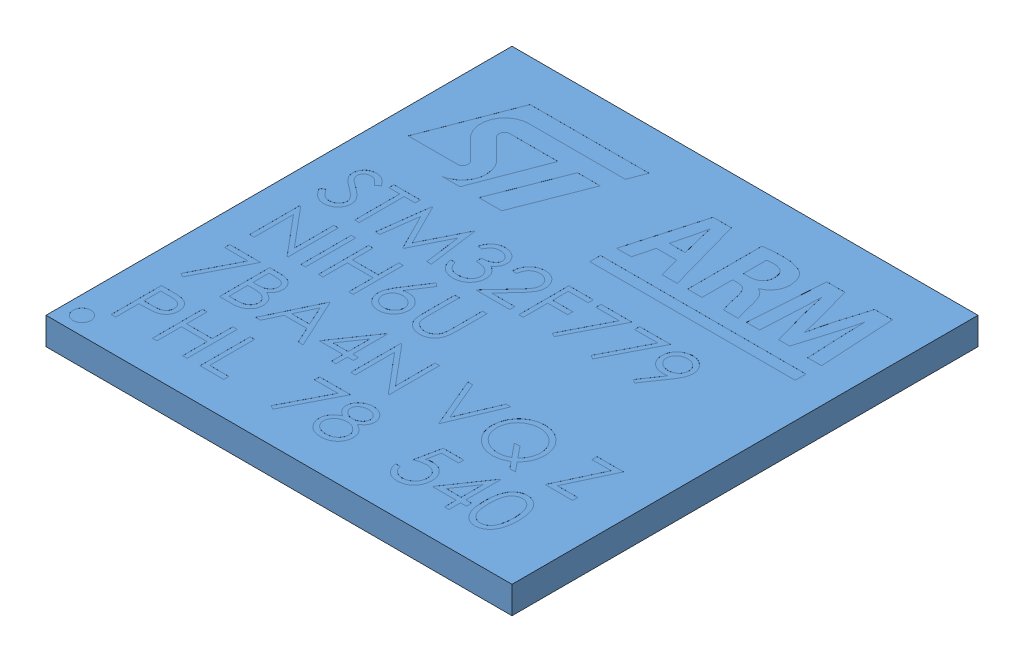
SolidWorks assembly STM32F779NIHx, configuration Default. Lengths in mm.
Overall size (13 0.96 13).
217 component instances, 2 part files, 3 mates.
Components (placement in the parent):
- Part1-1: Part1 [Default] at (-6.3865 6.105 16.3707) size (13 0.76 13)
- ball-1: ball [Default] at (5.7135 6.105 15.4707) x (-0.992109 0 0.125382) z (0.125382 0 0.992109) size (0.4 0.2 0.4)
- ball-2: ball [Default] at (4.9135 6.105 15.4707) x (-0.992109 0 0.125382) z (0.125382 0 0.992109) size (0.4 0.2 0.4)
- ball-3: ball [Default] at (4.1135 6.105 15.4707) x (-0.992109 0 0.125382) z (0.125382 0 0.992109) size (0.4 0.2 0.4)
- ball-4: ball [Default] at (3.3135 6.105 15.4707) x (-0.992109 0 0.125382) z (0.125382 0 0.992109) size (0.4 0.2 0.4)
- ball-5: ball [Default] at (2.5135 6.105 15.4707) x (-0.992109 0 0.125382) z (0.125382 0 0.992109) size (0.4 0.2 0.4)
- ball-6: ball [Default] at (1.7135 6.105 15.4707) x (-0.992109 0 0.125382) z (0.125382 0 0.992109) size (0.4 0.2 0.4)
- ball-7: ball [Default] at (0.9135 6.105 15.4707) x (-0.992109 0 0.125382) z (0.125382 0 0.992109) size (0.4 0.2 0.4)
- ball-8: ball [Default] at (0.1135 6.105 15.4707) x (-0.992109 0 0.125382) z (0.125382 0 0.992109) size (0.4 0.2 0.4)
- ball-9: ball [Default] at (-0.6865 6.105 15.4707) x (-0.992109 0 0.125382) z (0.125382 0 0.992109) size (0.4 0.2 0.4)
- ball-10: ball [Default] at (-1.4865 6.105 15.4707) x (-0.992109 0 0.125382) z (0.125382 0 0.992109) size (0.4 0.2 0.4)
- ball-11: ball [Default] at (-2.2865 6.105 15.4707) x (-0.992109 0 0.125382) z (0.125382 0 0.992109) size (0.4 0.2 0.4)
- ball-12: ball [Default] at (-3.0865 6.105 15.4707) x (-0.992109 0 0.125382) z (0.125382 0 0.992109) size (0.4 0.2 0.4)
- ball-13: ball [Default] at (-3.8865 6.105 15.4707) x (-0.992109 0 0.125382) z (0.125382 0 0.992109) size (0.4 0.2 0.4)
- ball-14: ball [Default] at (-4.6865 6.105 15.4707) x (-0.992109 0 0.125382) z (0.125382 0 0.992109) size (0.4 0.2 0.4)
- ball-15: ball [Default] at (-5.4865 6.105 15.4707) x (-0.992109 0 0.125382) z (0.125382 0 0.992109) size (0.4 0.2 0.4)
- ball-16: ball [Default] at (5.7135 6.105 14.6707) x (-0.992109 0 0.125382) z (0.125382 0 0.992109) size (0.4 0.2 0.4)
- ball-17: ball [Default] at (5.7135 6.105 13.8707) x (-0.992109 0 0.125382) z (0.125382 0 0.992109) size (0.4 0.2 0.4)
- ball-18: ball [Default] at (5.7135 6.105 13.0707) x (-0.992109 0 0.125382) z (0.125382 0 0.992109) size (0.4 0.2 0.4)
- ball-19: ball [Default] at (5.7135 6.105 12.2707) x (-0.992109 0 0.125382) z (0.125382 0 0.992109) size (0.4 0.2 0.4)
- ball-20: ball [Default] at (5.7135 6.105 11.4707) x (-0.992109 0 0.125382) z (0.125382 0 0.992109) size (0.4 0.2 0.4)
- ball-21: ball [Default] at (5.7135 6.105 10.6707) x (-0.992109 0 0.125382) z (0.125382 0 0.992109) size (0.4 0.2 0.4)
- ball-22: ball [Default] at (5.7135 6.105 9.8707) x (-0.992109 0 0.125382) z (0.125382 0 0.992109) size (0.4 0.2 0.4)
- ball-23: ball [Default] at (5.7135 6.105 9.0707) x (-0.992109 0 0.125382) z (0.125382 0 0.992109) size (0.4 0.2 0.4)
- ball-24: ball [Default] at (5.7135 6.105 8.2707) x (-0.992109 0 0.125382) z (0.125382 0 0.992109) size (0.4 0.2 0.4)
- ball-25: ball [Default] at (5.7135 6.105 7.4707) x (-0.992109 0 0.125382) z (0.125382 0 0.992109) size (0.4 0.2 0.4)
- ball-26: ball [Default] at (5.7135 6.105 6.6707) x (-0.992109 0 0.125382) z (0.125382 0 0.992109) size (0.4 0.2 0.4)
- ball-27: ball [Default] at (5.7135 6.105 5.8707) x (-0.992109 0 0.125382) z (0.125382 0 0.992109) size (0.4 0.2 0.4)
- ball-28: ball [Default] at (5.7135 6.105 5.0707) x (-0.992109 0 0.125382) z (0.125382 0 0.992109) size (0.4 0.2 0.4)
- ball-29: ball [Default] at (5.7135 6.105 4.2707) x (-0.992109 0 0.125382) z (0.125382 0 0.992109) size (0.4 0.2 0.4)
- ball-30: ball [Default] at (4.9135 6.105 14.6707) x (-0.992109 0 0.125382) z (0.125382 0 0.992109) size (0.4 0.2 0.4)
- ball-31: ball [Default] at (4.9135 6.105 13.8707) x (-0.992109 0 0.125382) z (0.125382 0 0.992109) size (0.4 0.2 0.4)
- ball-32: ball [Default] at (4.9135 6.105 13.0707) x (-0.992109 0 0.125382) z (0.125382 0 0.992109) size (0.4 0.2 0.4)
- ball-33: ball [Default] at (4.9135 6.105 12.2707) x (-0.992109 0 0.125382) z (0.125382 0 0.992109) size (0.4 0.2 0.4)
- ball-34: ball [Default] at (4.9135 6.105 11.4707) x (-0.992109 0 0.125382) z (0.125382 0 0.992109) size (0.4 0.2 0.4)
- ball-35: ball [Default] at (4.9135 6.105 10.6707) x (-0.992109 0 0.125382) z (0.125382 0 0.992109) size (0.4 0.2 0.4)
- ball-36: ball [Default] at (4.9135 6.105 9.8707) x (-0.992109 0 0.125382) z (0.125382 0 0.992109) size (0.4 0.2 0.4)
- ball-37: ball [Default] at (4.9135 6.105 9.0707) x (-0.992109 0 0.125382) z (0.125382 0 0.992109) size (0.4 0.2 0.4)
- ball-38: ball [Default] at (4.9135 6.105 8.2707) x (-0.992109 0 0.125382) z (0.125382 0 0.992109) size (0.4 0.2 0.4)
- ball-39: ball [Default] at (4.9135 6.105 7.4707) x (-0.992109 0 0.125382) z (0.125382 0 0.992109) size (0.4 0.2 0.4)
- ball-40: ball [Default] at (4.9135 6.105 6.6707) x (-0.992109 0 0.125382) z (0.125382 0 0.992109) size (0.4 0.2 0.4)
- ball-41: ball [Default] at (4.9135 6.105 5.8707) x (-0.992109 0 0.125382) z (0.125382 0 0.992109) size (0.4 0.2 0.4)
- ball-42: ball [Default] at (4.9135 6.105 5.0707) x (-0.992109 0 0.125382) z (0.125382 0 0.992109) size (0.4 0.2 0.4)
- ball-43: ball [Default] at (4.9135 6.105 4.2707) x (-0.992109 0 0.125382) z (0.125382 0 0.992109) size (0.4 0.2 0.4)
- ball-44: ball [Default] at (4.1135 6.105 14.6707) x (-0.992109 0 0.125382) z (0.125382 0 0.992109) size (0.4 0.2 0.4)
- ball-45: ball [Default] at (4.1135 6.105 13.8707) x (-0.992109 0 0.125382) z (0.125382 0 0.992109) size (0.4 0.2 0.4)
- ball-46: ball [Default] at (4.1135 6.105 13.0707) x (-0.992109 0 0.125382) z (0.125382 0 0.992109) size (0.4 0.2 0.4)
- ball-47: ball [Default] at (4.1135 6.105 12.2707) x (-0.992109 0 0.125382) z (0.125382 0 0.992109) size (0.4 0.2 0.4)
- ball-48: ball [Default] at (4.1135 6.105 11.4707) x (-0.992109 0 0.125382) z (0.125382 0 0.992109) size (0.4 0.2 0.4)
- ball-49: ball [Default] at (4.1135 6.105 10.6707) x (-0.992109 0 0.125382) z (0.125382 0 0.992109) size (0.4 0.2 0.4)
- ball-50: ball [Default] at (4.1135 6.105 9.8707) x (-0.992109 0 0.125382) z (0.125382 0 0.992109) size (0.4 0.2 0.4)
- ball-51: ball [Default] at (4.1135 6.105 9.0707) x (-0.992109 0 0.125382) z (0.125382 0 0.992109) size (0.4 0.2 0.4)
- ball-52: ball [Default] at (4.1135 6.105 8.2707) x (-0.992109 0 0.125382) z (0.125382 0 0.992109) size (0.4 0.2 0.4)
- ball-53: ball [Default] at (4.1135 6.105 7.4707) x (-0.992109 0 0.125382) z (0.125382 0 0.992109) size (0.4 0.2 0.4)
- ball-54: ball [Default] at (4.1135 6.105 6.6707) x (-0.992109 0 0.125382) z (0.125382 0 0.992109) size (0.4 0.2 0.4)
- ball-55: ball [Default] at (4.1135 6.105 5.8707) x (-0.992109 0 0.125382) z (0.125382 0 0.992109) size (0.4 0.2 0.4)
- ball-56: ball [Default] at (4.1135 6.105 5.0707) x (-0.992109 0 0.125382) z (0.125382 0 0.992109) size (0.4 0.2 0.4)
- ball-57: ball [Default] at (4.1135 6.105 4.2707) x (-0.992109 0 0.125382) z (0.125382 0 0.992109) size (0.4 0.2 0.4)
- ball-58: ball [Default] at (3.3135 6.105 14.6707) x (-0.992109 0 0.125382) z (0.125382 0 0.992109) size (0.4 0.2 0.4)
- ball-59: ball [Default] at (3.3135 6.105 13.8707) x (-0.992109 0 0.125382) z (0.125382 0 0.992109) size (0.4 0.2 0.4)
- ball-60: ball [Default] at (3.3135 6.105 13.0707) x (-0.992109 0 0.125382) z (0.125382 0 0.992109) size (0.4 0.2 0.4)
- ball-61: ball [Default] at (3.3135 6.105 12.2707) x (-0.992109 0 0.125382) z (0.125382 0 0.992109) size (0.4 0.2 0.4)
- ball-62: ball [Default] at (3.3135 6.105 11.4707) x (-0.992109 0 0.125382) z (0.125382 0 0.992109) size (0.4 0.2 0.4)
- ball-63: ball [Default] at (3.3135 6.105 10.6707) x (-0.992109 0 0.125382) z (0.125382 0 0.992109) size (0.4 0.2 0.4)
- ball-64: ball [Default] at (3.3135 6.105 9.8707) x (-0.992109 0 0.125382) z (0.125382 0 0.992109) size (0.4 0.2 0.4)
- ball-65: ball [Default] at (3.3135 6.105 9.0707) x (-0.992109 0 0.125382) z (0.125382 0 0.992109) size (0.4 0.2 0.4)
- ball-66: ball [Default] at (3.3135 6.105 8.2707) x (-0.992109 0 0.125382) z (0.125382 0 0.992109) size (0.4 0.2 0.4)
- ball-67: ball [Default] at (3.3135 6.105 7.4707) x (-0.992109 0 0.125382) z (0.125382 0 0.992109) size (0.4 0.2 0.4)
- ball-68: ball [Default] at (3.3135 6.105 6.6707) x (-0.992109 0 0.125382) z (0.125382 0 0.992109) size (0.4 0.2 0.4)
- ball-69: ball [Default] at (3.3135 6.105 5.8707) x (-0.992109 0 0.125382) z (0.125382 0 0.992109) size (0.4 0.2 0.4)
- ball-70: ball [Default] at (3.3135 6.105 5.0707) x (-0.992109 0 0.125382) z (0.125382 0 0.992109) size (0.4 0.2 0.4)
- ball-71: ball [Default] at (3.3135 6.105 4.2707) x (-0.992109 0 0.125382) z (0.125382 0 0.992109) size (0.4 0.2 0.4)
- ball-72: ball [Default] at (2.5135 6.105 14.6707) x (-0.992109 0 0.125382) z (0.125382 0 0.992109) size (0.4 0.2 0.4)
- ball-73: ball [Default] at (2.5135 6.105 13.8707) x (-0.992109 0 0.125382) z (0.125382 0 0.992109) size (0.4 0.2 0.4)
- ball-74: ball [Default] at (2.5135 6.105 13.0707) x (-0.992109 0 0.125382) z (0.125382 0 0.992109) size (0.4 0.2 0.4)
- ball-75: ball [Default] at (2.5135 6.105 12.2707) x (-0.992109 0 0.125382) z (0.125382 0 0.992109) size (0.4 0.2 0.4)
- ball-76: ball [Default] at (2.5135 6.105 11.4707) x (-0.992109 0 0.125382) z (0.125382 0 0.992109) size (0.4 0.2 0.4)
- ball-77: ball [Default] at (2.5135 6.105 10.6707) x (-0.992109 0 0.125382) z (0.125382 0 0.992109) size (0.4 0.2 0.4)
- ball-78: ball [Default] at (2.5135 6.105 9.8707) x (-0.992109 0 0.125382) z (0.125382 0 0.992109) size (0.4 0.2 0.4)
- ball-79: ball [Default] at (2.5135 6.105 9.0707) x (-0.992109 0 0.125382) z (0.125382 0 0.992109) size (0.4 0.2 0.4)
- ball-80: ball [Default] at (2.5135 6.105 8.2707) x (-0.992109 0 0.125382) z (0.125382 0 0.992109) size (0.4 0.2 0.4)
- ball-81: ball [Default] at (2.5135 6.105 7.4707) x (-0.992109 0 0.125382) z (0.125382 0 0.992109) size (0.4 0.2 0.4)
- ball-82: ball [Default] at (2.5135 6.105 6.6707) x (-0.992109 0 0.125382) z (0.125382 0 0.992109) size (0.4 0.2 0.4)
- ball-83: ball [Default] at (2.5135 6.105 5.8707) x (-0.992109 0 0.125382) z (0.125382 0 0.992109) size (0.4 0.2 0.4)
- ball-84: ball [Default] at (2.5135 6.105 5.0707) x (-0.992109 0 0.125382) z (0.125382 0 0.992109) size (0.4 0.2 0.4)
- ball-85: ball [Default] at (2.5135 6.105 4.2707) x (-0.992109 0 0.125382) z (0.125382 0 0.992109) size (0.4 0.2 0.4)
- ball-86: ball [Default] at (1.7135 6.105 14.6707) x (-0.992109 0 0.125382) z (0.125382 0 0.992109) size (0.4 0.2 0.4)
- ball-87: ball [Default] at (1.7135 6.105 13.8707) x (-0.992109 0 0.125382) z (0.125382 0 0.992109) size (0.4 0.2 0.4)
- ball-88: ball [Default] at (1.7135 6.105 13.0707) x (-0.992109 0 0.125382) z (0.125382 0 0.992109) size (0.4 0.2 0.4)
- ball-89: ball [Default] at (1.7135 6.105 12.2707) x (-0.992109 0 0.125382) z (0.125382 0 0.992109) size (0.4 0.2 0.4)
- ball-90: ball [Default] at (1.7135 6.105 11.4707) x (-0.992109 0 0.125382) z (0.125382 0 0.992109) size (0.4 0.2 0.4)
- ball-91: ball [Default] at (1.7135 6.105 10.6707) x (-0.992109 0 0.125382) z (0.125382 0 0.992109) size (0.4 0.2 0.4)
- ball-92: ball [Default] at (1.7135 6.105 9.8707) x (-0.992109 0 0.125382) z (0.125382 0 0.992109) size (0.4 0.2 0.4)
- ball-93: ball [Default] at (1.7135 6.105 9.0707) x (-0.992109 0 0.125382) z (0.125382 0 0.992109) size (0.4 0.2 0.4)
- ball-94: ball [Default] at (1.7135 6.105 8.2707) x (-0.992109 0 0.125382) z (0.125382 0 0.992109) size (0.4 0.2 0.4)
- ball-95: ball [Default] at (1.7135 6.105 7.4707) x (-0.992109 0 0.125382) z (0.125382 0 0.992109) size (0.4 0.2 0.4)
- ball-96: ball [Default] at (1.7135 6.105 6.6707) x (-0.992109 0 0.125382) z (0.125382 0 0.992109) size (0.4 0.2 0.4)
- ball-97: ball [Default] at (1.7135 6.105 5.8707) x (-0.992109 0 0.125382) z (0.125382 0 0.992109) size (0.4 0.2 0.4)
- ball-98: ball [Default] at (1.7135 6.105 5.0707) x (-0.992109 0 0.125382) z (0.125382 0 0.992109) size (0.4 0.2 0.4)
- ball-99: ball [Default] at (1.7135 6.105 4.2707) x (-0.992109 0 0.125382) z (0.125382 0 0.992109) size (0.4 0.2 0.4)
- ball-100: ball [Default] at (0.9135 6.105 14.6707) x (-0.992109 0 0.125382) z (0.125382 0 0.992109) size (0.4 0.2 0.4)
- ball-101: ball [Default] at (0.9135 6.105 13.8707) x (-0.992109 0 0.125382) z (0.125382 0 0.992109) size (0.4 0.2 0.4)
- ball-102: ball [Default] at (0.9135 6.105 13.0707) x (-0.992109 0 0.125382) z (0.125382 0 0.992109) size (0.4 0.2 0.4)
- ball-103: ball [Default] at (0.9135 6.105 12.2707) x (-0.992109 0 0.125382) z (0.125382 0 0.992109) size (0.4 0.2 0.4)
- ball-104: ball [Default] at (0.9135 6.105 11.4707) x (-0.992109 0 0.125382) z (0.125382 0 0.992109) size (0.4 0.2 0.4)
- ball-108: ball [Default] at (0.9135 6.105 8.2707) x (-0.992109 0 0.125382) z (0.125382 0 0.992109) size (0.4 0.2 0.4)
- ball-109: ball [Default] at (0.9135 6.105 7.4707) x (-0.992109 0 0.125382) z (0.125382 0 0.992109) size (0.4 0.2 0.4)
- ball-110: ball [Default] at (0.9135 6.105 6.6707) x (-0.992109 0 0.125382) z (0.125382 0 0.992109) size (0.4 0.2 0.4)
- ball-111: ball [Default] at (0.9135 6.105 5.8707) x (-0.992109 0 0.125382) z (0.125382 0 0.992109) size (0.4 0.2 0.4)
- ball-112: ball [Default] at (0.9135 6.105 5.0707) x (-0.992109 0 0.125382) z (0.125382 0 0.992109) size (0.4 0.2 0.4)
- ball-113: ball [Default] at (0.9135 6.105 4.2707) x (-0.992109 0 0.125382) z (0.125382 0 0.992109) size (0.4 0.2 0.4)
- ball-114: ball [Default] at (0.1135 6.105 14.6707) x (-0.992109 0 0.125382) z (0.125382 0 0.992109) size (0.4 0.2 0.4)
- ball-115: ball [Default] at (0.1135 6.105 13.8707) x (-0.992109 0 0.125382) z (0.125382 0 0.992109) size (0.4 0.2 0.4)
- ball-116: ball [Default] at (0.1135 6.105 13.0707) x (-0.992109 0 0.125382) z (0.125382 0 0.992109) size (0.4 0.2 0.4)
- ball-117: ball [Default] at (0.1135 6.105 12.2707) x (-0.992109 0 0.125382) z (0.125382 0 0.992109) size (0.4 0.2 0.4)
- ball-118: ball [Default] at (0.1135 6.105 11.4707) x (-0.992109 0 0.125382) z (0.125382 0 0.992109) size (0.4 0.2 0.4)
- ball-122: ball [Default] at (0.1135 6.105 8.2707) x (-0.992109 0 0.125382) z (0.125382 0 0.992109) size (0.4 0.2 0.4)
- ball-123: ball [Default] at (0.1135 6.105 7.4707) x (-0.992109 0 0.125382) z (0.125382 0 0.992109) size (0.4 0.2 0.4)
- ball-124: ball [Default] at (0.1135 6.105 6.6707) x (-0.992109 0 0.125382) z (0.125382 0 0.992109) size (0.4 0.2 0.4)
- ball-125: ball [Default] at (0.1135 6.105 5.8707) x (-0.992109 0 0.125382) z (0.125382 0 0.992109) size (0.4 0.2 0.4)
- ball-126: ball [Default] at (0.1135 6.105 5.0707) x (-0.992109 0 0.125382) z (0.125382 0 0.992109) size (0.4 0.2 0.4)
- ball-127: ball [Default] at (0.1135 6.105 4.2707) x (-0.992109 0 0.125382) z (0.125382 0 0.992109) size (0.4 0.2 0.4)
- ball-128: ball [Default] at (-0.6865 6.105 14.6707) x (-0.992109 0 0.125382) z (0.125382 0 0.992109) size (0.4 0.2 0.4)
- ball-129: ball [Default] at (-0.6865 6.105 13.8707) x (-0.992109 0 0.125382) z (0.125382 0 0.992109) size (0.4 0.2 0.4)
- ball-130: ball [Default] at (-0.6865 6.105 13.0707) x (-0.992109 0 0.125382) z (0.125382 0 0.992109) size (0.4 0.2 0.4)
- ball-131: ball [Default] at (-0.6865 6.105 12.2707) x (-0.992109 0 0.125382) z (0.125382 0 0.992109) size (0.4 0.2 0.4)
- ball-132: ball [Default] at (-0.6865 6.105 11.4707) x (-0.992109 0 0.125382) z (0.125382 0 0.992109) size (0.4 0.2 0.4)
- ball-136: ball [Default] at (-0.6865 6.105 8.2707) x (-0.992109 0 0.125382) z (0.125382 0 0.992109) size (0.4 0.2 0.4)
- ball-137: ball [Default] at (-0.6865 6.105 7.4707) x (-0.992109 0 0.125382) z (0.125382 0 0.992109) size (0.4 0.2 0.4)
- ball-138: ball [Default] at (-0.6865 6.105 6.6707) x (-0.992109 0 0.125382) z (0.125382 0 0.992109) size (0.4 0.2 0.4)
- ball-139: ball [Default] at (-0.6865 6.105 5.8707) x (-0.992109 0 0.125382) z (0.125382 0 0.992109) size (0.4 0.2 0.4)
- ball-140: ball [Default] at (-0.6865 6.105 5.0707) x (-0.992109 0 0.125382) z (0.125382 0 0.992109) size (0.4 0.2 0.4)
- ball-141: ball [Default] at (-0.6865 6.105 4.2707) x (-0.992109 0 0.125382) z (0.125382 0 0.992109) size (0.4 0.2 0.4)
- ball-142: ball [Default] at (-1.4865 6.105 14.6707) x (-0.992109 0 0.125382) z (0.125382 0 0.992109) size (0.4 0.2 0.4)
- ball-143: ball [Default] at (-1.4865 6.105 13.8707) x (-0.992109 0 0.125382) z (0.125382 0 0.992109) size (0.4 0.2 0.4)
- ball-144: ball [Default] at (-1.4865 6.105 13.0707) x (-0.992109 0 0.125382) z (0.125382 0 0.992109) size (0.4 0.2 0.4)
- ball-145: ball [Default] at (-1.4865 6.105 12.2707) x (-0.992109 0 0.125382) z (0.125382 0 0.992109) size (0.4 0.2 0.4)
- ball-146: ball [Default] at (-1.4865 6.105 11.4707) x (-0.992109 0 0.125382) z (0.125382 0 0.992109) size (0.4 0.2 0.4)
- ball-147: ball [Default] at (-1.4865 6.105 10.6707) x (-0.992109 0 0.125382) z (0.125382 0 0.992109) size (0.4 0.2 0.4)
- ball-148: ball [Default] at (-1.4865 6.105 9.8707) x (-0.992109 0 0.125382) z (0.125382 0 0.992109) size (0.4 0.2 0.4)
- ball-149: ball [Default] at (-1.4865 6.105 9.0707) x (-0.992109 0 0.125382) z (0.125382 0 0.992109) size (0.4 0.2 0.4)
- ball-150: ball [Default] at (-1.4865 6.105 8.2707) x (-0.992109 0 0.125382) z (0.125382 0 0.992109) size (0.4 0.2 0.4)
- ball-151: ball [Default] at (-1.4865 6.105 7.4707) x (-0.992109 0 0.125382) z (0.125382 0 0.992109) size (0.4 0.2 0.4)
- ball-152: ball [Default] at (-1.4865 6.105 6.6707) x (-0.992109 0 0.125382) z (0.125382 0 0.992109) size (0.4 0.2 0.4)
- ball-153: ball [Default] at (-1.4865 6.105 5.8707) x (-0.992109 0 0.125382) z (0.125382 0 0.992109) size (0.4 0.2 0.4)
- ball-154: ball [Default] at (-1.4865 6.105 5.0707) x (-0.992109 0 0.125382) z (0.125382 0 0.992109) size (0.4 0.2 0.4)
- ball-155: ball [Default] at (-1.4865 6.105 4.2707) x (-0.992109 0 0.125382) z (0.125382 0 0.992109) size (0.4 0.2 0.4)
- ball-156: ball [Default] at (-2.2865 6.105 14.6707) x (-0.992109 0 0.125382) z (0.125382 0 0.992109) size (0.4 0.2 0.4)
- ball-157: ball [Default] at (-2.2865 6.105 13.8707) x (-0.992109 0 0.125382) z (0.125382 0 0.992109) size (0.4 0.2 0.4)
- ball-158: ball [Default] at (-2.2865 6.105 13.0707) x (-0.992109 0 0.125382) z (0.125382 0 0.992109) size (0.4 0.2 0.4)
- ball-159: ball [Default] at (-2.2865 6.105 12.2707) x (-0.992109 0 0.125382) z (0.125382 0 0.992109) size (0.4 0.2 0.4)
- ball-160: ball [Default] at (-2.2865 6.105 11.4707) x (-0.992109 0 0.125382) z (0.125382 0 0.992109) size (0.4 0.2 0.4)
- ball-161: ball [Default] at (-2.2865 6.105 10.6707) x (-0.992109 0 0.125382) z (0.125382 0 0.992109) size (0.4 0.2 0.4)
- ball-162: ball [Default] at (-2.2865 6.105 9.8707) x (-0.992109 0 0.125382) z (0.125382 0 0.992109) size (0.4 0.2 0.4)
- ball-163: ball [Default] at (-2.2865 6.105 9.0707) x (-0.992109 0 0.125382) z (0.125382 0 0.992109) size (0.4 0.2 0.4)
- ball-164: ball [Default] at (-2.2865 6.105 8.2707) x (-0.992109 0 0.125382) z (0.125382 0 0.992109) size (0.4 0.2 0.4)
- ball-165: ball [Default] at (-2.2865 6.105 7.4707) x (-0.992109 0 0.125382) z (0.125382 0 0.992109) size (0.4 0.2 0.4)
- ball-166: ball [Default] at (-2.2865 6.105 6.6707) x (-0.992109 0 0.125382) z (0.125382 0 0.992109) size (0.4 0.2 0.4)
- ball-167: ball [Default] at (-2.2865 6.105 5.8707) x (-0.992109 0 0.125382) z (0.125382 0 0.992109) size (0.4 0.2 0.4)
- ball-168: ball [Default] at (-2.2865 6.105 5.0707) x (-0.992109 0 0.125382) z (0.125382 0 0.992109) size (0.4 0.2 0.4)
- ball-169: ball [Default] at (-2.2865 6.105 4.2707) x (-0.992109 0 0.125382) z (0.125382 0 0.992109) size (0.4 0.2 0.4)
- ball-170: ball [Default] at (-3.0865 6.105 14.6707) x (-0.992109 0 0.125382) z (0.125382 0 0.992109) size (0.4 0.2 0.4)
- ball-171: ball [Default] at (-3.0865 6.105 13.8707) x (-0.992109 0 0.125382) z (0.125382 0 0.992109) size (0.4 0.2 0.4)
- ball-172: ball [Default] at (-3.0865 6.105 13.0707) x (-0.992109 0 0.125382) z (0.125382 0 0.992109) size (0.4 0.2 0.4)
- ball-173: ball [Default] at (-3.0865 6.105 12.2707) x (-0.992109 0 0.125382) z (0.125382 0 0.992109) size (0.4 0.2 0.4)
- ball-174: ball [Default] at (-3.0865 6.105 11.4707) x (-0.992109 0 0.125382) z (0.125382 0 0.992109) size (0.4 0.2 0.4)
- ball-175: ball [Default] at (-3.0865 6.105 10.6707) x (-0.992109 0 0.125382) z (0.125382 0 0.992109) size (0.4 0.2 0.4)
- ball-176: ball [Default] at (-3.0865 6.105 9.8707) x (-0.992109 0 0.125382) z (0.125382 0 0.992109) size (0.4 0.2 0.4)
- ball-177: ball [Default] at (-3.0865 6.105 9.0707) x (-0.992109 0 0.125382) z (0.125382 0 0.992109) size (0.4 0.2 0.4)
- ball-178: ball [Default] at (-3.0865 6.105 8.2707) x (-0.992109 0 0.125382) z (0.125382 0 0.992109) size (0.4 0.2 0.4)
- ball-179: ball [Default] at (-3.0865 6.105 7.4707) x (-0.992109 0 0.125382) z (0.125382 0 0.992109) size (0.4 0.2 0.4)
- ball-180: ball [Default] at (-3.0865 6.105 6.6707) x (-0.992109 0 0.125382) z (0.125382 0 0.992109) size (0.4 0.2 0.4)
- ball-181: ball [Default] at (-3.0865 6.105 5.8707) x (-0.992109 0 0.125382) z (0.125382 0 0.992109) size (0.4 0.2 0.4)
- ball-182: ball [Default] at (-3.0865 6.105 5.0707) x (-0.992109 0 0.125382) z (0.125382 0 0.992109) size (0.4 0.2 0.4)
- ball-183: ball [Default] at (-3.0865 6.105 4.2707) x (-0.992109 0 0.125382) z (0.125382 0 0.992109) size (0.4 0.2 0.4)
- ball-184: ball [Default] at (-3.8865 6.105 14.6707) x (-0.992109 0 0.125382) z (0.125382 0 0.992109) size (0.4 0.2 0.4)
- ball-185: ball [Default] at (-3.8865 6.105 13.8707) x (-0.992109 0 0.125382) z (0.125382 0 0.992109) size (0.4 0.2 0.4)
- ball-186: ball [Default] at (-3.8865 6.105 13.0707) x (-0.992109 0 0.125382) z (0.125382 0 0.992109) size (0.4 0.2 0.4)
- ball-187: ball [Default] at (-3.8865 6.105 12.2707) x (-0.992109 0 0.125382) z (0.125382 0 0.992109) size (0.4 0.2 0.4)
- ball-188: ball [Default] at (-3.8865 6.105 11.4707) x (-0.992109 0 0.125382) z (0.125382 0 0.992109) size (0.4 0.2 0.4)
- ball-189: ball [Default] at (-3.8865 6.105 10.6707) x (-0.992109 0 0.125382) z (0.125382 0 0.992109) size (0.4 0.2 0.4)
- ball-190: ball [Default] at (-3.8865 6.105 9.8707) x (-0.992109 0 0.125382) z (0.125382 0 0.992109) size (0.4 0.2 0.4)
- ball-191: ball [Default] at (-3.8865 6.105 9.0707) x (-0.992109 0 0.125382) z (0.125382 0 0.992109) size (0.4 0.2 0.4)
- ball-192: ball [Default] at (-3.8865 6.105 8.2707) x (-0.992109 0 0.125382) z (0.125382 0 0.992109) size (0.4 0.2 0.4)
- ball-193: ball [Default] at (-3.8865 6.105 7.4707) x (-0.992109 0 0.125382) z (0.125382 0 0.992109) size (0.4 0.2 0.4)
- ball-194: ball [Default] at (-3.8865 6.105 6.6707) x (-0.992109 0 0.125382) z (0.125382 0 0.992109) size (0.4 0.2 0.4)
- ball-195: ball [Default] at (-3.8865 6.105 5.8707) x (-0.992109 0 0.125382) z (0.125382 0 0.992109) size (0.4 0.2 0.4)
- ball-196: ball [Default] at (-3.8865 6.105 5.0707) x (-0.992109 0 0.125382) z (0.125382 0 0.992109) size (0.4 0.2 0.4)
- ball-197: ball [Default] at (-3.8865 6.105 4.2707) x (-0.992109 0 0.125382) z (0.125382 0 0.992109) size (0.4 0.2 0.4)
- ball-198: ball [Default] at (-4.6865 6.105 14.6707) x (-0.992109 0 0.125382) z (0.125382 0 0.992109) size (0.4 0.2 0.4)
- ball-199: ball [Default] at (-4.6865 6.105 13.8707) x (-0.992109 0 0.125382) z (0.125382 0 0.992109) size (0.4 0.2 0.4)
- ball-200: ball [Default] at (-4.6865 6.105 13.0707) x (-0.992109 0 0.125382) z (0.125382 0 0.992109) size (0.4 0.2 0.4)
- ball-201: ball [Default] at (-4.6865 6.105 12.2707) x (-0.992109 0 0.125382) z (0.125382 0 0.992109) size (0.4 0.2 0.4)
- ball-202: ball [Default] at (-4.6865 6.105 11.4707) x (-0.992109 0 0.125382) z (0.125382 0 0.992109) size (0.4 0.2 0.4)
- ball-203: ball [Default] at (-4.6865 6.105 10.6707) x (-0.992109 0 0.125382) z (0.125382 0 0.992109) size (0.4 0.2 0.4)
- ball-204: ball [Default] at (-4.6865 6.105 9.8707) x (-0.992109 0 0.125382) z (0.125382 0 0.992109) size (0.4 0.2 0.4)
- ball-205: ball [Default] at (-4.6865 6.105 9.0707) x (-0.992109 0 0.125382) z (0.125382 0 0.992109) size (0.4 0.2 0.4)
- ball-206: ball [Default] at (-4.6865 6.105 8.2707) x (-0.992109 0 0.125382) z (0.125382 0 0.992109) size (0.4 0.2 0.4)
- ball-207: ball [Default] at (-4.6865 6.105 7.4707) x (-0.992109 0 0.125382) z (0.125382 0 0.992109) size (0.4 0.2 0.4)
- ball-208: ball [Default] at (-4.6865 6.105 6.6707) x (-0.992109 0 0.125382) z (0.125382 0 0.992109) size (0.4 0.2 0.4)
- ball-209: ball [Default] at (-4.6865 6.105 5.8707) x (-0.992109 0 0.125382) z (0.125382 0 0.992109) size (0.4 0.2 0.4)
- ball-210: ball [Default] at (-4.6865 6.105 5.0707) x (-0.992109 0 0.125382) z (0.125382 0 0.992109) size (0.4 0.2 0.4)
- ball-211: ball [Default] at (-4.6865 6.105 4.2707) x (-0.992109 0 0.125382) z (0.125382 0 0.992109) size (0.4 0.2 0.4)
- ball-212: ball [Default] at (-5.4865 6.105 14.6707) x (-0.992109 0 0.125382) z (0.125382 0 0.992109) size (0.4 0.2 0.4)
- ball-213: ball [Default] at (-5.4865 6.105 13.8707) x (-0.992109 0 0.125382) z (0.125382 0 0.992109) size (0.4 0.2 0.4)
- ball-214: ball [Default] at (-5.4865 6.105 13.0707) x (-0.992109 0 0.125382) z (0.125382 0 0.992109) size (0.4 0.2 0.4)
- ball-215: ball [Default] at (-5.4865 6.105 12.2707) x (-0.992109 0 0.125382) z (0.125382 0 0.992109) size (0.4 0.2 0.4)
- ball-216: ball [Default] at (-5.4865 6.105 11.4707) x (-0.992109 0 0.125382) z (0.125382 0 0.992109) size (0.4 0.2 0.4)
- ball-217: ball [Default] at (-5.4865 6.105 10.6707) x (-0.992109 0 0.125382) z (0.125382 0 0.992109) size (0.4 0.2 0.4)
- ball-218: ball [Default] at (-5.4865 6.105 9.8707) x (-0.992109 0 0.125382) z (0.125382 0 0.992109) size (0.4 0.2 0.4)
- ball-219: ball [Default] at (-5.4865 6.105 9.0707) x (-0.992109 0 0.125382) z (0.125382 0 0.992109) size (0.4 0.2 0.4)
- ball-220: ball [Default] at (-5.4865 6.105 8.2707) x (-0.992109 0 0.125382) z (0.125382 0 0.992109) size (0.4 0.2 0.4)
- ball-221: ball [Default] at (-5.4865 6.105 7.4707) x (-0.992109 0 0.125382) z (0.125382 0 0.992109) size (0.4 0.2 0.4)
- ball-222: ball [Default] at (-5.4865 6.105 6.6707) x (-0.992109 0 0.125382) z (0.125382 0 0.992109) size (0.4 0.2 0.4)
- ball-223: ball [Default] at (-5.4865 6.105 5.8707) x (-0.992109 0 0.125382) z (0.125382 0 0.992109) size (0.4 0.2 0.4)
- ball-224: ball [Default] at (-5.4865 6.105 5.0707) x (-0.992109 0 0.125382) z (0.125382 0 0.992109) size (0.4 0.2 0.4)
- ball-225: ball [Default] at (-5.4865 6.105 4.2707) x (-0.992109 0 0.125382) z (0.125382 0 0.992109) size (0.4 0.2 0.4)
Mates (geometry in assembly coordinates):
- Coincident1: coincident anti-aligned: plane of Part1-1 through (-6.3865 6.105 16.3707) normal (0 -1 0); plane of ball-1 through (5.7135 6.105 15.4707) normal (0 1 0)
- Distance2: distance = 0.7 mm aligned: plane of Part1-1 through (6.6135 6.865 16.3707) normal (1 0 0); sphere of ball-1
- Distance3: distance = 0.7 mm aligned: plane of Part1-1 through (-6.3865 6.865 16.3707) normal (0 0 1); sphere of ball-1
